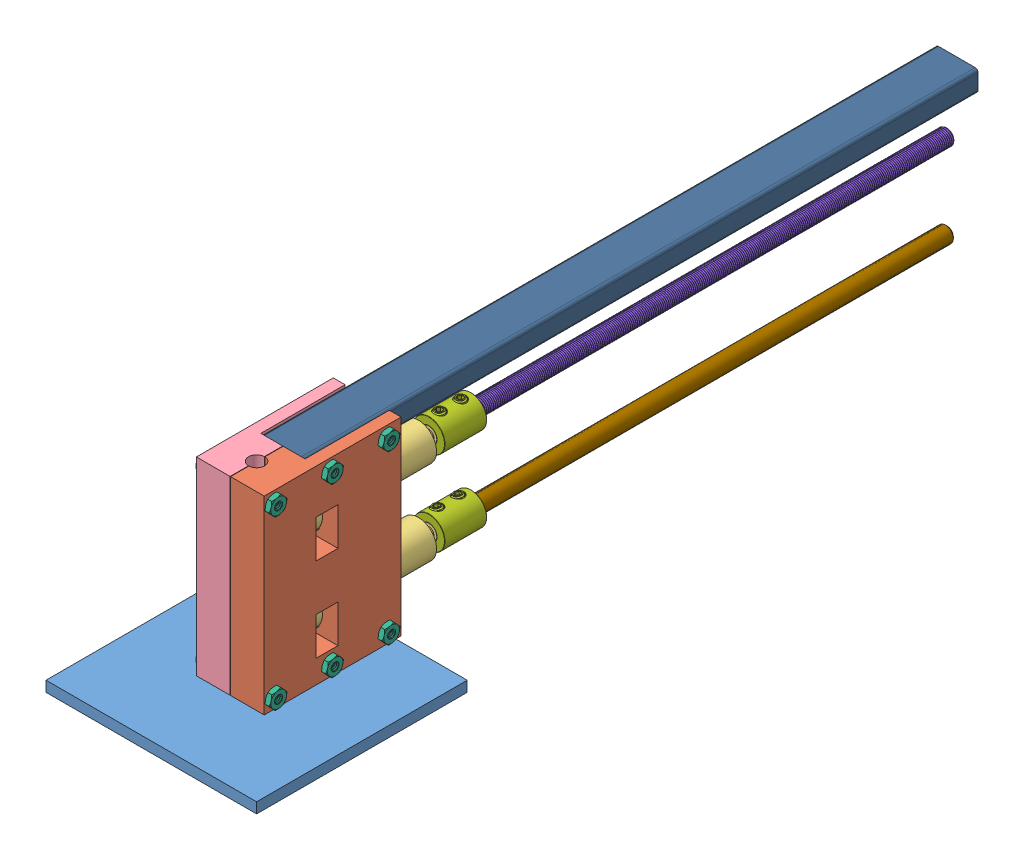
SolidWorks assembly Plotter_v2, configuration Default. Lengths in mm.
Overall size (127 120.96 485.78).
22 component instances, 10 part files, 28 mates.
Components (placement in the parent):
- Base-1: Base [Default] at origin size (127 107.95 127)
- Motor Mount-1: Motor Mount [Default] at (20.447 57.15 -66.675) x (0 1 0) z (0 0 1) size (114.3 20.32 82.55)
- Motor-1: Motor [Default] at (0.127 82.55 -15.875) x (0 -1 0) z (0 0 -1) size (21.97 25.4 95.5)
- Motor-3: Motor [Default] at (0.127 31.75 -15.875) x (0 -1 0) z (0 0 -1) size (21.97 25.4 95.5)
- Motor Mount Wire Side-4: Motor Mount Wire Side [Wire Side] at (-20.447 57.15 -66.675) x (0 -1 0) z (0 0 1) size (114.3 20.32 82.55)
- #10 Phillips Screw-1: #10 Phillips Screw [90272A251] at (-3.0861 114.3 -57.785) x (0 0 1) z (-1 0 0) size (9.47 9.47 41.69)
- #10 Steel Hex Nut-1: #10 Steel Hex Nut [90480A011] at (22.0345 114.3 -57.785) x (0 -0.294341 -0.9557) z (0 -0.9557 0.294341) size (9.53 3.99 11)
- #10 Steel Hex Nut-2: #10 Steel Hex Nut [90480A011] at (22.0345 114.3 -23.7177) x (0 -0.294341 -0.9557) z (0 -0.9557 0.294341) size (9.53 3.99 11)
- #10 Steel Hex Nut-3: #10 Steel Hex Nut [90480A011] at (22.0345 114.3 10.3497) x (0 -0.294341 -0.9557) z (0 -0.9557 0.294341) size (9.53 3.99 11)
- #10 Phillips Screw-2: #10 Phillips Screw [90272A251] at (-3.0861 114.3 -23.7177) x (0 0 1) z (-1 0 0) size (9.47 9.47 41.69)
- #10 Phillips Screw-3: #10 Phillips Screw [90272A251] at (-3.0861 114.3 10.3497) x (0 0 1) z (-1 0 0) size (9.47 9.47 41.69)
- #10 Phillips Screw-4: #10 Phillips Screw [90272A251] at (-3.0861 13.335 -57.785) x (0 0 1) z (-1 0 0) size (9.47 9.47 41.69)
- #10 Phillips Screw-6: #10 Phillips Screw [90272A251] at (-3.0861 13.335 -23.7177) x (0 0 1) z (-1 0 0) size (9.47 9.47 41.69)
- #10 Phillips Screw-8: #10 Phillips Screw [90272A251] at (-3.0861 13.335 10.3497) x (0 0 1) z (-1 0 0) size (9.47 9.47 41.69)
- #10 Steel Hex Nut-4: #10 Steel Hex Nut [90480A011] at (22.0345 13.335 -57.785) x (0 -0.294341 -0.9557) z (0 -0.9557 0.294341) size (9.53 3.99 11)
- #10 Steel Hex Nut-6: #10 Steel Hex Nut [90480A011] at (22.0345 13.335 -23.7177) x (0 -0.294341 -0.9557) z (0 -0.9557 0.294341) size (9.53 3.99 11)
- #10 Steel Hex Nut-8: #10 Steel Hex Nut [90480A011] at (22.0345 13.335 10.3497) x (0 -0.294341 -0.9557) z (0 -0.9557 0.294341) size (9.53 3.99 11)
- Set Screw Shaft Coupling-1: Set Screw Shaft Coupling [6412K13] at (0.127 82.55 -116.459) size (19.05 20.32 25.4)
- Set Screw Shaft Coupling-2: Set Screw Shaft Coupling [6412K13] at (0.127 31.75 -116.459) x (0.987351 0.158553 0) z (0 0 1) size (19.05 20.32 25.4)
- .375 Steel Threaded Rod-1: .375 Steel Threaded Rod [98791A051] at (0.127 82.55 -111.379) size (10 9.69 305.84)
- Rotary Shaft-1: Rotary Shaft [1346K11] at (0.127 31.75 -263.779) size (9.53 9.53 304.8)
- T-Slotted Framing Rail-1: T-Slotted Framing Rail [6575N215] at (0 120.65 -219.075) x (-1 0 0) z (0 0 1) size (25.4 12.7 406.4)
Mates (geometry in assembly coordinates):
- Coincident1: coordinate: unknown of Base-1
- Coincident2: coincident: plane of Base-1 through (0 6.35 0) normal (0 1 0); plane of Motor Mount-1 through (20.447 6.35 -28.575) normal (0 -1 0)
- Concentric1: concentric: cylinder of Base-1 through (0 107.95 0) axis (0 -1 0) radius 4.7625; cylinder of Motor Mount-1 through (0 134.3 0) axis (0 -1 0) radius 4.826
- Coincident5: coincident: plane of Motor Mount-1 through (9.017 89.7342 -28.575) normal (-1 0 0); plane of Motor-1 through (9.525 88.2385 -72.009) normal (1 0 0)
- Coincident6: coincident: plane of Motor Mount-1 through (46.8483 93.98 -28.575) normal (0 0 1); plane of Motor-1 through (0.127 82.55 -28.575) normal (0 0 -1)
- Concentric2: concentric: cylinder of Motor Mount-1 through (0.127 82.55 -28.575) axis (0 0 -1) radius 11.43; cylinder of Motor-1 through (0.127 82.55 -28.575) axis (0 0 1) radius 10.9855
- Coincident9: coincident: plane of Motor Mount-1 through (9.017 24.5658 -28.575) normal (-1 0 0); plane of Motor-3 through (9.525 37.4385 -72.009) normal (1 0 0)
- Coincident10: coincident: plane of Motor Mount-1 through (46.8483 20.32 -28.575) normal (0 0 1); plane of Motor-3 through (0.127 31.75 -28.575) normal (0 0 -1)
- Concentric3: concentric: cylinder of Motor Mount-1 through (0.127 31.75 -28.575) axis (0 0 -1) radius 11.43; cylinder of Motor-3 through (0.127 31.75 -28.575) axis (0 0 1) radius 10.9855
- Coincident23: coincident: plane of Motor Mount-1 through (0.127 6.35 -28.575) normal (-1 0 0); plane of Motor Mount Wire Side-4 through (-0.127 107.95 -28.575) normal (1 0 0)
- Coincident24: coincident: plane of Base-1 through (0 6.35 0) normal (0 1 0); plane of Motor Mount Wire Side-4 through (-20.447 6.35 -28.575) normal (0 -1 0)
- Concentric8: concentric: cylinder of Base-1 through (0 107.95 0) axis (0 -1 0) radius 4.7625; cylinder of Motor Mount Wire Side-4 through (0 -7.3 0) axis (0 1 0) radius 4.826
- Coincident25: coincident: plane of Motor Mount Wire Side-4 through (-20.447 107.95 -28.575) normal (-1 0 0); plane of #10 Phillips Screw-1 through (-20.447 114.3 -53.2892) normal (1 0 0)
- Concentric9: concentric: cylinder of Motor Mount Wire Side-4 through (-0.127 114.3 -57.785) axis (1 0 0) radius 2.4574; cylinder of #10 Phillips Screw-1 through (-23.8252 114.3 -57.785) axis (-1 0 0) radius 2.413
- Concentric10: concentric anti-aligned: cylinder of #10 Phillips Screw-1 through (-23.8252 114.3 -57.785) axis (-1 0 0) radius 2.413; circle of #10 Steel Hex Nut-1
- Coincident26: coincident anti-aligned: plane of Motor Mount-1 through (20.447 6.35 -28.575) normal (1 0 0); plane of #10 Steel Hex Nut-1 through (20.447 118.3296 -54.0428) normal (-1 0 0)
- Concentric11: concentric anti-aligned: cylinder of Motor-1 through (0.127 82.55 -111.379) axis (0 0 1) radius 4.7625; cylinder of Set Screw Shaft Coupling-1 through (0.127 82.55 -103.759) axis (0 0 -1) radius 4.7625
- Coincident27: coincident aligned: plane of Motor-1 through (0.127 82.55 -103.759) normal (0 0 1); plane of Set Screw Shaft Coupling-1 through (0.127 82.55 -103.759) normal (0 0 1)
- Concentric12: concentric anti-aligned: cylinder of Motor-3 through (0.127 31.75 -111.379) axis (0 0 1) radius 4.7625; cylinder of Set Screw Shaft Coupling-2 through (0.127 31.75 -103.759) axis (0 0 -1) radius 4.7625
- Coincident28: coincident aligned: plane of Motor-3 through (0.127 31.75 -103.759) normal (0 0 1); plane of Set Screw Shaft Coupling-2 through (0.127 31.75 -103.759) normal (0 0 1)
- Coincident29: coincident anti-aligned: plane of Motor-1 through (0.127 82.55 -111.379) normal (0 0 -1); plane of .375 Steel Threaded Rod-1 through (0.127 82.55 -111.379) normal (0 0 1)
- Concentric13: concentric anti-aligned: cylinder of Set Screw Shaft Coupling-1 through (0.127 82.55 -103.759) axis (0 0 -1) radius 4.7625; cylinder of .375 Steel Threaded Rod-1 through (0.127 82.55 -111.379) axis (0 0 1) radius 4.7625
- Coincident30: coincident anti-aligned: plane of Motor-3 through (0.127 31.75 -111.379) normal (0 0 -1); plane of Rotary Shaft-1 through (0.127 31.75 -111.379) normal (0 0 1)
- Concentric14: concentric aligned: cylinder of Set Screw Shaft Coupling-2 through (0.127 31.75 -103.759) axis (0 0 -1) radius 4.7625; cylinder of Rotary Shaft-1 through (0.127 31.75 -111.379) axis (0 0 -1) radius 4.7625
- Coincident31: coincident: plane of Motor Mount-1 through (20.447 107.95 -28.575) normal (0 1 0); plane of T-Slotted Framing Rail-1 through (-3.302 107.95 -15.875) normal (0 -1 0)
- Parallel1: parallel: plane of Motor Mount-1 through (20.447 57.15 15.875) normal (0 0 1); plane of T-Slotted Framing Rail-1 through (11.049 109.601 -15.875) normal (0 0 1)
- Width1: width: plane of Motor Mount-1 through (13.335 120.65 -66.675) normal (-1 0 0); plane of T-Slotted Framing Rail-1 through (-13.335 120.65 -66.675) normal (1 0 0); plane of Motor Mount Wire Side-4 through (-12.7 118.999 -15.875) normal (-1 0 0); plane of T-Slotted Framing Rail-1 through (12.7 109.601 -15.875) normal (1 0 0)
- Coincident33: coincident: plane of Motor Mount Wire Side-4 through (-20.447 120.65 -15.875) normal (0 0 -1); plane of T-Slotted Framing Rail-1 through (11.049 109.601 -15.875) normal (0 0 1)
